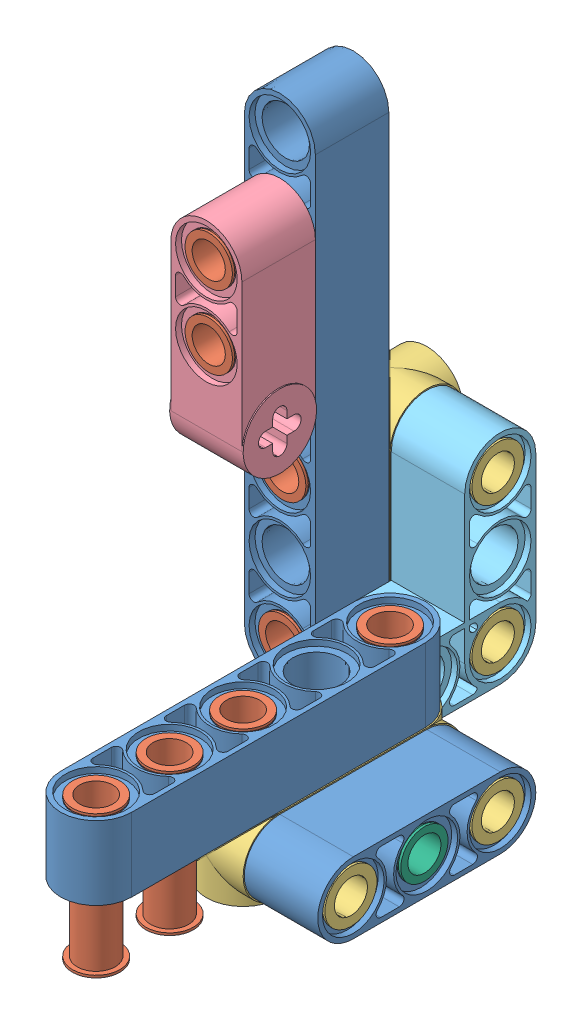
SolidWorks assembly right_rider_bottom, configuration Default. Lengths in mm.
Overall size (39.12 54.99 54.99).
16 component instances, 6 part files, 48 mates.
Components (placement in the parent):
- All_Straight-1: All_Straight [Seven] x (0 1 0) z (0 0 1) size (54.86 7.62 7.87)
- BlackConnectorSmall-1: BlackConnectorSmall [Default] at (0 0 15.494) x (0 0 -1) z (1 0 0) size (15.24 5.59 5.59)
- BlackConnectorSmall-3: BlackConnectorSmall [Default] at (0 -7.874 15.494) x (0 0 -1) z (1 0 0) size (15.24 5.59 5.59)
- BlackConnectorSmall-4: BlackConnectorSmall [Default] at (0 -23.622 -7.62) x (0 0 1) z (1 0 0) size (15.24 5.59 5.59)
- BlackConnectorSmall-5: BlackConnectorSmall [Default] at (0 -39.37 -7.62) x (0 0 1) z (1 0 0) size (15.24 5.59 5.59)
- Light_Gray_X1-1: Light_Gray_X1 [Default] at (3.937 -31.496 -3.937) x (0 1 0) z (0 0 1) size (23.62 23.11 7.87)
- StraightTurn_Twohole_1Cross-1: StraightTurn_Twohole_1Cross [Default] at (3.81 -7.747 11.811) x (0 -1 0) z (-1 0 0) size (23.5 7.87 7.87)
- L_Three_Five_90degrees-1: L_Three_Five_90degrees [Default] at (4.191 -39.37 3.937) x (0 0 -1) z (1 0 0) size (39.12 23.37 7.87)
- Light_Gray_X1-2: Light_Gray_X1 [Default] at (19.685 -39.37 19.685) x (0 0 -1) z (0 1 0) size (23.62 23.11 7.87)
- BlueConnectorLong-1: BlueConnectorLong [Default] at (27.305 -39.37 19.685) x (-1 0 0) z (0 0 -1) size (22.86 5.59 5.59)
- BlackConnectorSmall-6: BlackConnectorSmall [Default] at (15.748 -27.813 11.811) x (0 -1 0) z (0 0 1) size (15.24 5.59 5.59)
- BlackConnectorSmall-7: BlackConnectorSmall [Default] at (15.748 -27.813 27.559) x (0 -1 0) z (0 0 1) size (15.24 5.59 5.59)
- All_Straight-2: All_Straight [Five] at (15.748 -35.433 19.685) x (0 0 -1) z (0 1 0) size (39.12 7.62 7.87)
- All_Straight-3: All_Straight [Three] at (27.559 -39.37 19.685) x (0 0 -1) z (-1 0 0) size (23.37 7.62 7.87)
- BlackConnectorSmall-8: BlackConnectorSmall [Default] at (15.748 -27.813 43.307) x (0 -1 0) z (0 0 1) size (15.24 5.59 5.59)
- BlackConnectorSmall-9: BlackConnectorSmall [Default] at (15.748 -27.813 35.433) x (0 -1 0) z (0 0 1) size (15.24 5.59 5.59)
Mates (geometry in assembly coordinates):
- Coincident1: coincident aligned: plane of All_Straight-1; plane of assembly through (0 0 0) normal (0 1 0)
- Coincident2: coincident anti-aligned: plane of All_Straight-1; plane of assembly through (0 0 0) normal (1 0 0)
- Coincident3: coincident aligned: plane of All_Straight-1 through (0 0 0) normal (0 0 1); plane of assembly through (0 0 0) normal (0 0 1)
- Concentric1: concentric anti-aligned: cylinder of All_Straight-1 through (0 0 3.937) axis (0 0 -1) radius 2.54; cylinder of BlackConnectorSmall-1 through (0 0 15.494) axis (0 0 1) radius 2.032
- Coincident4: coincident anti-aligned: plane of All_Straight-1 through (0 0 7.239) normal (0 0 1); plane of BlackConnectorSmall-1 through (0 2.032 7.239) normal (0 0 -1)
- Coincident5: coincident aligned: plane of BlackConnectorSmall-1 through (0 0 15.494) normal (1 0 0); plane of assembly through (0 0 0) normal (1 0 0)
- Concentric3: concentric anti-aligned: cylinder of All_Straight-1 through (0 -7.874 3.937) axis (0 0 -1) radius 2.54; cylinder of BlackConnectorSmall-3 through (0 -7.874 15.494) axis (0 0 1) radius 2.032
- Coincident7: coincident anti-aligned: plane of All_Straight-1 through (0 -7.874 7.239) normal (0 0 1); plane of BlackConnectorSmall-3 through (0 -5.842 7.239) normal (0 0 -1)
- Coincident8: coincident aligned: plane of BlackConnectorSmall-3 through (0 -7.874 15.494) normal (1 0 0); plane of assembly through (0 0 0) normal (1 0 0)
- Concentric4: concentric aligned: cylinder of All_Straight-1 through (0 -23.622 3.937) axis (0 0 -1) radius 2.54; cylinder of BlackConnectorSmall-4 through (0 -23.622 -7.62) axis (0 0 -1) radius 2.032
- Coincident9: coincident anti-aligned: plane of All_Straight-1 through (0 -23.622 0.635) normal (0 0 -1); plane of BlackConnectorSmall-4 through (0 -25.654 0.635) normal (0 0 1)
- Coincident10: coincident aligned: plane of BlackConnectorSmall-4 through (0 -23.622 -7.62) normal (1 0 0); plane of assembly through (0 0 0) normal (1 0 0)
- Concentric8: concentric aligned: cylinder of All_Straight-1 through (0 -39.37 3.937) axis (0 0 -1) radius 2.54; cylinder of BlackConnectorSmall-5 through (0 -39.37 -7.62) axis (0 0 -1) radius 2.032
- Coincident13: coincident anti-aligned: plane of All_Straight-1 through (0 -39.37 0.635) normal (0 0 -1); plane of BlackConnectorSmall-5 through (0 -41.402 0.635) normal (0 0 1)
- Coincident14: coincident aligned: plane of BlackConnectorSmall-5 through (0 -39.37 -7.62) normal (1 0 0); plane of assembly through (0 0 0) normal (1 0 0)
- Concentric10: concentric anti-aligned: cylinder of BlackConnectorSmall-4 through (0 -23.622 -7.62) axis (0 0 -1) radius 2.032; cylinder of Light_Gray_X1-1 through (0 -23.622 -7.874) axis (0 0 1) radius 2.286
- Concentric11: concentric anti-aligned: cylinder of BlackConnectorSmall-5 through (0 -39.37 -7.62) axis (0 0 -1) radius 2.032; cylinder of Light_Gray_X1-1 through (0 -39.37 -7.874) axis (0 0 1) radius 2.286
- Coincident16: coincident anti-aligned: plane of BlackConnectorSmall-4 through (0 -26.416 -0.635) normal (0 0 -1); plane of Light_Gray_X1-1 through (0 -23.622 -0.635) normal (0 0 1)
- Concentric12: concentric anti-aligned: cylinder of BlackConnectorSmall-1 through (0 0 15.494) axis (0 0 1) radius 2.032; cylinder of StraightTurn_Twohole_1Cross-1 through (0 0 11.811) axis (0 0 -1) radius 2.54
- Concentric13: concentric anti-aligned: cylinder of BlackConnectorSmall-3 through (0 -7.874 15.494) axis (0 0 1) radius 2.032; cylinder of StraightTurn_Twohole_1Cross-1 through (0 -7.874 11.811) axis (0 0 -1) radius 2.54
- Coincident17: coincident anti-aligned: plane of BlackConnectorSmall-1 through (0 2.794 8.509) normal (0 0 1); plane of StraightTurn_Twohole_1Cross-1 through (0 0 8.509) normal (0 0 -1)
- Parallel1: parallel aligned: plane of BlueConnectorLong-1; plane of assembly through (0 0 0) normal (0 1 0)
- Parallel2: parallel aligned: plane of BlackConnectorSmall-6 through (15.748 -27.813 11.811) normal (0 0 1); plane of assembly through (0 0 0) normal (0 0 1)
- Parallel3: parallel aligned: plane of BlackConnectorSmall-7; plane of assembly through (0 0 0) normal (1 0 0)
- Concentric25: concentric aligned: cylinder of Light_Gray_X1-1 through (11.557 -23.622 -3.937) axis (-1 0 0) radius 2.032; cylinder of L_Three_Five_90degrees-1 through (8.001 -23.622 -3.937) axis (-1 0 0) radius 2.54
- Concentric26: concentric aligned: cylinder of Light_Gray_X1-1 through (11.557 -39.37 -3.937) axis (-1 0 0) radius 2.032; cylinder of L_Three_Five_90degrees-1 through (8.001 -39.37 -3.937) axis (-1 0 0) radius 2.54
- Coincident25: coincident anti-aligned: plane of Light_Gray_X1-1 through (4.572 -23.622 -3.937) normal (1 0 0); plane of L_Three_Five_90degrees-1 through (4.572 -23.622 -3.937) normal (-1 0 0)
- Parallel4: parallel aligned: plane of BlackConnectorSmall-8 through (15.748 -27.813 43.307) normal (0 0 1); plane of assembly through (0 0 0) normal (0 0 1)
- Parallel5: parallel aligned: plane of BlackConnectorSmall-9 through (15.748 -27.813 35.433) normal (0 0 1); plane of assembly through (0 0 0) normal (0 0 1)
- Concentric37: concentric anti-aligned: cylinder of L_Three_Five_90degrees-1 through (8.001 -39.37 11.811) axis (-1 0 0) radius 2.54; cylinder of Light_Gray_X1-2 through (4.191 -39.37 11.811) axis (1 0 0) radius 2.032
- Concentric38: concentric anti-aligned: cylinder of L_Three_Five_90degrees-1 through (8.001 -39.37 27.559) axis (-1 0 0) radius 2.54; cylinder of Light_Gray_X1-2 through (4.191 -39.37 27.559) axis (1 0 0) radius 2.032
- Coincident41: coincident anti-aligned: plane of L_Three_Five_90degrees-1 through (11.176 -39.37 11.811) normal (1 0 0); plane of Light_Gray_X1-2 through (11.176 -39.37 11.811) normal (-1 0 0)
- Concentric39: concentric aligned: cylinder of Light_Gray_X1-2 through (15.748 -43.307 11.811) axis (0 1 0) radius 2.286; cylinder of BlackConnectorSmall-6 through (15.748 -27.813 11.811) axis (0 1 0) radius 2.032
- Coincident42: coincident anti-aligned: plane of Light_Gray_X1-2 through (15.748 -36.068 11.811) normal (0 1 0); plane of BlackConnectorSmall-6 through (17.78 -36.068 11.811) normal (0 -1 0)
- Concentric40: concentric aligned: cylinder of Light_Gray_X1-2 through (15.748 -43.307 27.559) axis (0 1 0) radius 2.286; cylinder of BlackConnectorSmall-7 through (15.748 -27.813 27.559) axis (0 1 0) radius 2.032
- Coincident43: coincident anti-aligned: plane of Light_Gray_X1-2 through (15.748 -36.068 27.559) normal (0 1 0); plane of BlackConnectorSmall-7 through (17.78 -36.068 27.559) normal (0 -1 0)
- Concentric41: concentric anti-aligned: cylinder of Light_Gray_X1-2 through (19.304 -39.37 19.685) axis (-1 0 0) radius 2.54; cylinder of BlueConnectorLong-1 through (27.305 -39.37 19.685) axis (1 0 0) radius 2.032
- Coincident44: coincident anti-aligned: plane of Light_Gray_X1-2 through (19.05 -39.37 19.685) normal (1 0 0); plane of BlueConnectorLong-1 through (19.05 -37.338 19.685) normal (-1 0 0)
- Concentric42: concentric anti-aligned: cylinder of BlackConnectorSmall-6 through (15.748 -27.813 11.811) axis (0 1 0) radius 2.032; cylinder of All_Straight-2 through (15.748 -31.496 11.811) axis (0 -1 0) radius 2.54
- Concentric43: concentric anti-aligned: cylinder of BlackConnectorSmall-7 through (15.748 -27.813 27.559) axis (0 1 0) radius 2.032; cylinder of All_Straight-2 through (15.748 -31.496 27.559) axis (0 -1 0) radius 2.54
- Coincident45: coincident anti-aligned: plane of BlackConnectorSmall-6 through (18.542 -34.798 11.811) normal (0 1 0); plane of All_Straight-2 through (15.748 -34.798 11.811) normal (0 -1 0)
- Concentric44: concentric anti-aligned: cylinder of Light_Gray_X1-2 through (27.305 -39.37 11.811) axis (-1 0 0) radius 2.032; cylinder of All_Straight-3 through (23.622 -39.37 11.811) axis (1 0 0) radius 2.54
- Concentric45: concentric anti-aligned: cylinder of Light_Gray_X1-2 through (27.305 -39.37 27.559) axis (-1 0 0) radius 2.032; cylinder of All_Straight-3 through (23.622 -39.37 27.559) axis (1 0 0) radius 2.54
- Coincident46: coincident anti-aligned: plane of Light_Gray_X1-2 through (20.32 -39.37 11.811) normal (1 0 0); plane of All_Straight-3 through (20.32 -39.37 11.811) normal (-1 0 0)
- Concentric46: concentric anti-aligned: cylinder of All_Straight-2 through (15.748 -31.496 35.433) axis (0 -1 0) radius 2.54; cylinder of BlackConnectorSmall-9 through (15.748 -27.813 35.433) axis (0 1 0) radius 2.032
- Coincident47: coincident anti-aligned: plane of All_Straight-2 through (15.748 -34.798 35.433) normal (0 -1 0); plane of BlackConnectorSmall-9 through (18.542 -34.798 35.433) normal (0 1 0)
- Concentric47: concentric anti-aligned: cylinder of All_Straight-2 through (15.748 -31.496 43.307) axis (0 -1 0) radius 2.54; cylinder of BlackConnectorSmall-8 through (15.748 -27.813 43.307) axis (0 1 0) radius 2.032
- Coincident48: coincident anti-aligned: plane of All_Straight-2 through (15.748 -34.798 43.307) normal (0 -1 0); plane of BlackConnectorSmall-8 through (18.542 -34.798 43.307) normal (0 1 0)
